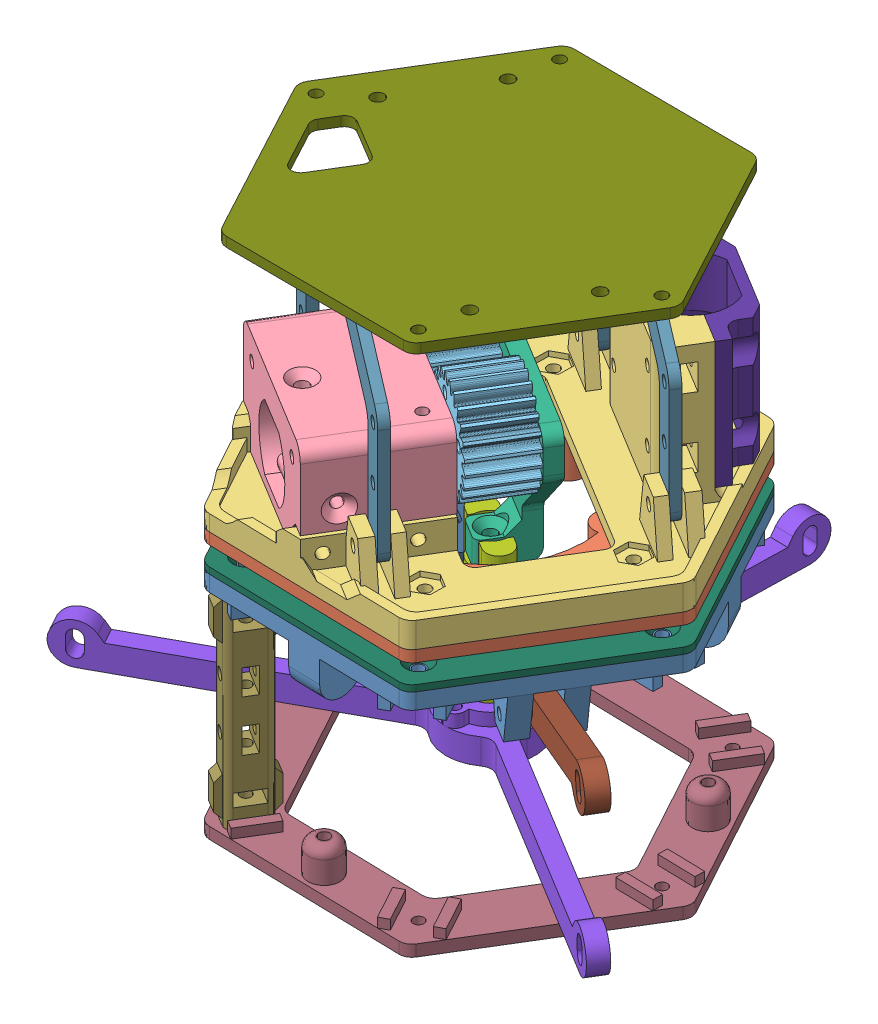
SolidWorks assembly Assem1, configuration Default. Lengths in mm.
Overall size (116.19 82.66 117.64).
19 component instances, 17 part files, 53 mates.
Components (placement in the parent):
- step-1: step [默认] at (-8.6911 34.9789 13.0706) x (-0.479213 0 -0.877699) z (0.877699 0 -0.479213) size (65.38 10 57.16)
- main2-1: main2 [默认] at (-8.6911 39.9789 13.0706) x (-0.520503 0 0.85386) z (-0.85386 0 -0.520503) size (65.38 6 57.16)
- main_copy-1: main_copy [默认] at (-8.6911 41.7789 13.0706) x (-0.520503 0 0.85386) z (-0.85386 0 -0.520503) size (65.38 24 57.16)
- main_engine_gear-1: main_engine_gear [默认] at (-12.3346 43.8789 19.0476) x (-0.520503 0 0.85386) z (-0.85386 0 -0.520503) size (18 16.5 27)
- gear_follow-1: gear_follow [默认] at (-1.8807 56.6477 20.15) x (0.278684 -0.945238 0.169882) z (0.520503 0 -0.85386) size (15.52 15.52 9)
- gear_follow-2: gear_follow [默认] at (-18.1041 56.6477 10.2604) x (0.278684 -0.945238 0.169882) z (0.520503 0 -0.85386) size (15.52 15.52 9)
- engine-1: engine [默认] at (-3.6146 58.2796 13.8229) x (0.520503 0 -0.85386) z (0.85386 0 0.520503) size (8 24.7 25)
- engine_rotate-1: engine_rotate [默认] at (-5.1761 15.9296 16.3844) x (-0.520503 0 0.85386) z (-0.85386 0 -0.520503) size (6 24 12)
- step_base-1: step_base [默认] at (-5.1761 11.9296 16.3844) x (0.520503 0 -0.85386) z (0.85386 0 0.520503) size (90.17 6.5 78.09)
- step_a-1: step_a [默认] at (-9.8724 17.9296 13.5217) x (0.520503 0 -0.85386) z (0.85386 0 0.520503) size (4.5 6.4 8.9)
- step_b-2: step_b [默认] at (-37.6821 26.0483 -3.7236) x (-0.520503 0 0.85386) z (0.851976 0.066397 0.519354) size (8.9 8.5 47.24)
- step_base_up-1: step_base_up [默认] at (11.2205 30.408 26.6139) x (0.520503 0 -0.85386) z (-0.823594 -0.263886 -0.502053) size (3 6.5 28.25)
- pillar-1: pillar [默认] at (-23.2652 33.4789 36.9787) x (-0.85386 0 -0.520503) z (-0.520503 0 0.85386) size (4.6 32 8)
- bottom-1: bottom [默认] at (-8.6911 -0.3211 13.0706) x (-0.479213 0 -0.877699) z (0.877699 0 -0.479213) size (65.38 6.8 57.16)
- support2-1: support2 [默认] at (-17.7999 48.7789 28.0131) x (0.520503 0 -0.85386) z (0.85386 0 0.520503) size (1.5 31.5 38.5)
- step_rotate_2-1: step_rotate_2 [默认] at (-8.6911 38.4789 13.0706) x (-0.479213 0 -0.877699) z (0 1 0) size (65.38 57.16 4)
- support2-2: support2 [默认] at (0.4177 48.7789 -1.872) x (-0.520503 0 0.85386) z (-0.85386 0 -0.520503) size (1.5 31.5 38.5)
- edison_platform-2: edison_platform [默认] at (-8.7975 81.7776 13.0057) x (0.520503 0 -0.85386) z (-0.853676 -0.020759 -0.520391) size (61.38 10.5 53.69)
- main_rotate_lock_2-1: main_rotate_lock_2 [默认] at (3.3845 65.7789 -6.739) x (-0.85386 0 -0.520503) z (-0.520503 0 0.85386) size (23 20 6.5)
Mates (geometry in assembly coordinates):
- Concentric5: concentric aligned: circle of main_copy-1; circle of main_engine_gear-1
- Concentric6: concentric aligned: circle of main_copy-1; circle of main_engine_gear-1
- Coincident3: coincident aligned: plane of main_copy-1 through (-17.0513 41.7789 19.1002) normal (0.85386 0 0.520503); plane of main_engine_gear-1 through (-17.0513 35.2789 19.1002) normal (0.85386 0 0.520503)
- Coincident4: coincident anti-aligned: plane of main_engine_gear-1 through (-12.3346 43.8789 19.0476) normal (0.520503 0 -0.85386); plane of gear_follow-1 through (-4.223 56.6477 23.9924) normal (-0.520503 0 0.85386)
- Concentric7: concentric anti-aligned: circle of main_engine_gear-1; circle of gear_follow-1
- Coincident5: coincident anti-aligned: plane of main_engine_gear-1 through (-12.3346 43.8789 19.0476) normal (0.520503 0 -0.85386); plane of gear_follow-2 through (-20.4463 56.6477 14.1028) normal (-0.520503 0 0.85386)
- Concentric8: concentric anti-aligned: circle of main_engine_gear-1; circle of gear_follow-2
- Coincident6: coincident anti-aligned: plane of gear_follow-1 through (0.4615 56.6477 16.3076) normal (0.520503 0 -0.85386); plane of engine-1 through (-3.6146 58.2796 13.8229) normal (-0.520503 0 0.85386)
- Concentric9: concentric anti-aligned: circle of gear_follow-1; circle of engine-1
- Concentric10: concentric anti-aligned: circle of gear_follow-2; circle of engine-1
- Parallel1: parallel aligned: plane of main_engine_gear-1 through (-33.2308 60.3789 27.3903) normal (0 1 0); plane of engine-1 through (8.3599 60.6296 18.1945) normal (0 1 0)
- Coincident8: coincident aligned: plane of step-1 through (-41.6818 33.4789 12.2839) normal (-0.85386 0 -0.520503); plane of main2-1 through (-24.5052 41.7789 -15.8935) normal (-0.85386 0 -0.520503)
- Coincident9: coincident anti-aligned: plane of engine-1 through (-4.3427 35.9296 19.8203) normal (0 -1 0); plane of engine_rotate-1 through (-5.1761 35.9296 16.3844) normal (0 1 0)
- Concentric11: concentric aligned: circle of engine-1; circle of engine_rotate-1
- Parallel2: parallel anti-aligned: plane of engine-1 through (-1.48 58.2796 15.1241) normal (0.85386 0 0.520503); plane of engine_rotate-1 through (-2.8707 39.9296 17.7898) normal (-0.85386 0 -0.520503)
- Coincident11: coincident anti-aligned: plane of engine_rotate-1 through (-5.1761 15.9296 16.3844) normal (0 -1 0); plane of step_base-1 through (-5.1761 15.9296 16.3844) normal (0 1 0)
- Concentric12: concentric aligned: circle of engine_rotate-1; circle of step_base-1
- Concentric13: concentric anti-aligned: circle of step_base-1; circle of step_a-1
- Coincident13: coincident anti-aligned: plane of step_base-1 through (-5.1761 17.9296 16.3844) normal (0 1 0); plane of step_a-1 through (-9.8724 17.9296 13.5217) normal (0 -1 0)
- Parallel4: parallel aligned: plane of step-1 through (-6.3909 34.9789 17.2835) normal (0.479213 0 0.877699); plane of step_base-1 through (-4.5052 11.9296 17.6132) normal (0.479213 0 0.877699)
- Parallel5: parallel aligned: plane of step-1 through (-31.5158 29.9789 2.0848) normal (-0.520503 0 0.85386); plane of step_a-1 through (-16.7217 20.9296 11.9815) normal (-0.520503 0 0.85386)
- Coincident16: coincident anti-aligned: plane of step_a-1 through (-16.7217 20.9296 11.9815) normal (-0.520503 0 0.85386); plane of step_b-2 through (-38.9833 26.0483 -1.589) normal (0.520503 0 -0.85386)
- Concentric15: concentric anti-aligned: circle of step_a-1; circle of step_b-2
- 重合7: coincident anti-aligned: plane of step-1 through (-7.7542 34.9789 11.5336) normal (-0.520503 0 0.85386); plane of step_base_up-1 through (13.2327 28.4789 24.327) normal (0.520503 0 -0.85386)
- 同心7: concentric anti-aligned: circle of step-1; circle of step_base_up-1
- 重合9: coincident anti-aligned: plane of step-1 through (-8.6911 33.4789 13.0706) normal (0 -1 0); plane of pillar-1 through (-23.2652 33.4789 36.9787) normal (0 1 0)
- 同心8: concentric anti-aligned: circle of step-1; circle of pillar-1
- 平行1: parallel anti-aligned: plane of step-1 through (-22.531 31.4789 40.5773) normal (-0.85386 0 -0.520503); plane of pillar-1 through (-19.7398 1.4789 35.6142) normal (0.85386 0 0.520503)
- 平行2: parallel anti-aligned: plane of step-1 through (-8.6911 33.4789 13.0706) normal (0 -1 0); plane of bottom-1 through (-8.6911 1.4789 13.0706) normal (0 1 0)
- 重合13: coincident anti-aligned: plane of pillar-1 through (-23.2652 1.4789 36.9787) normal (0 -1 0); plane of bottom-1 through (-8.6911 1.4789 13.0706) normal (0 1 0)
- 同心9: concentric anti-aligned: circle of pillar-1; circle of bottom-1
- 重合15: coincident aligned: plane of step-1 through (7.1229 33.4789 42.0346) normal (-0.023839 0 0.999716); plane of bottom-1 through (-25.8677 1.4789 41.2479) normal (-0.023839 0 0.999716)
- 平行4: parallel anti-aligned: plane of step-1 through (-8.6911 33.4789 13.0706) normal (0 -1 0); plane of assembly through (0 0 0) normal (0 1 0)
- 重合23: coincident anti-aligned: plane of main_copy-1 through (-17.0192 41.7789 26.7323) normal (-0.520503 0 0.85386); plane of support2-1 through (-2.5036 48.7789 35.5809) normal (0.520503 0 -0.85386)
- 同心13: concentric anti-aligned: circle of main_copy-1; circle of support2-1
- 同心14: concentric anti-aligned: circle of main_copy-1; circle of support2-1
- 重合26: coincident anti-aligned: plane of main2-1 through (-8.6911 41.7789 13.0706) normal (0 1 0); plane of main_copy-1 through (-8.6911 41.7789 13.0706) normal (0 -1 0)
- 同心18: concentric anti-aligned: circle of main2-1; circle of main_copy-1
- 同心19: concentric anti-aligned: circle of main2-1; circle of main_copy-1
- 重合28: coincident anti-aligned: plane of step-1 through (-8.6911 35.9789 13.0706) normal (0 1 0); plane of step_rotate_2-1 through (-8.6911 35.9789 13.0706) normal (0 -1 0)
- 重合29: coincident aligned: plane of step-1 through (7.1229 33.4789 42.0346) normal (-0.023839 0 0.999716); plane of step_rotate_2-1 through (7.1229 35.9789 42.0346) normal (-0.023839 0 0.999716)
- 重合30: coincident aligned: plane of step-1 through (24.2995 33.4789 13.8573) normal (0.85386 0 0.520503); plane of step_rotate_2-1 through (24.2995 35.9789 13.8573) normal (0.85386 0 0.520503)
- 同心20: concentric anti-aligned: circle of main2-1; circle of step_rotate_2-1
- 重合31: coincident anti-aligned: plane of main2-1 through (-8.6911 39.9789 13.0706) normal (0 -1 0); plane of step_rotate_2-1 through (-8.6911 39.9789 13.0706) normal (0 1 0)
- 相切2: tangent anti-aligned: cylinder of step-1 through (-31.5158 29.9789 2.0848) axis (0.520503 0 -0.85386) radius 3.3716; plane of step_b-2 through (-38.4108 26.0483 -2.5282) normal (-0.056693 0.997793 -0.03456)
- 重合32: coincident anti-aligned: plane of main_copy-1 through (-0.3631 41.7789 -0.5912) normal (0.520503 0 -0.85386); plane of support2-2 through (-14.8787 48.7789 -9.4397) normal (-0.520503 0 0.85386)
- 同心22: concentric aligned: circle of main_copy-1; circle of support2-2
- 同心23: concentric aligned: circle of main_copy-1; circle of support2-2
- 重合33: coincident anti-aligned: plane of support2-2 through (-14.8787 48.7789 -9.4397) normal (-0.520503 0 0.85386); plane of edison_platform-2 through (-0.4694 81.7776 -0.656) normal (0.520503 0 -0.85386)
- 同心24: concentric anti-aligned: circle of support2-2; circle of edison_platform-2
- 重合34: coincident aligned: plane of main_copy-1 through (3.3845 65.7789 -6.739) normal (0 1 0); plane of main_rotate_lock_2-1 through (3.3845 65.7789 -6.739) normal (0 1 0)
- 同心25: concentric anti-aligned: circle of main_copy-1; circle of main_rotate_lock_2-1
- 重合35: coincident anti-aligned: plane of main_copy-1 through (3.3845 97.806 -6.739) normal (0.520503 0 -0.85386); plane of main_rotate_lock_2-1 through (8.6358 45.7789 -3.5379) normal (-0.520503 0 0.85386)
